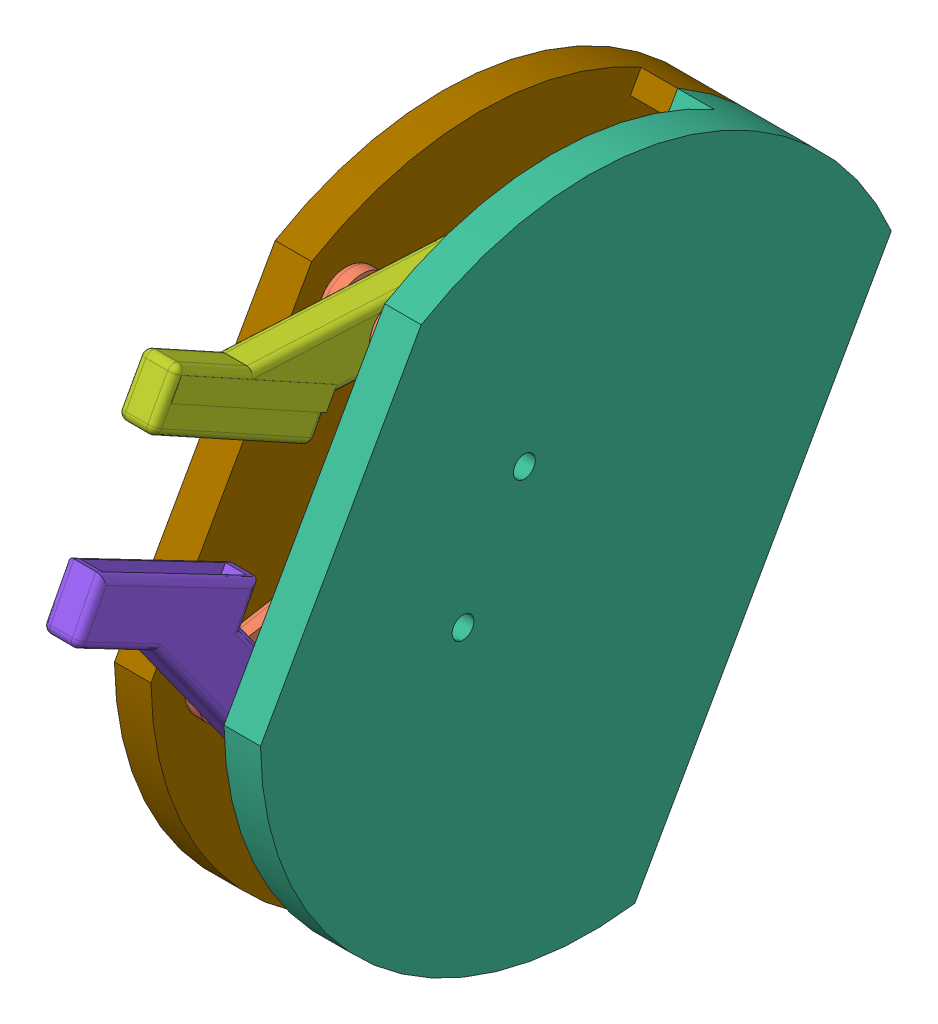
SolidWorks assembly 装配体1, configuration 默认. Lengths in mm.
Overall size (42.8 111.03 110.52).
10 component instances, 9 part files, 24 mates.
Components (placement in the parent):
- microservoArm-1: microservoArm [A3] at (-72.5456 -35.5156 22.831) x (0 -0.510048 -0.860146) z (0 0.860146 -0.510048) size (7.9 3.9 7)
- rod02-1: rod02 [默认] at (-67.7456 -24.2363 68.652) x (0 0.984777 0.173822) z (0 -0.173822 0.984777) size (8 10 28)
- microservoSG90-1: microservoSG90 [Default] at (-102.3456 -39.9562 25.3391) x (0 -0.870717 0.491784) z (0 0.491784 0.870717) size (32.3 29.8 12.5)
- 齿轮-2: 齿轮 [默认] at (-100.0187 -17.6428 -15.5872) x (1 0 0) z (0 -0.892437 -0.451172) size (10 44.73 18.87)
- 齿轮2-2: 齿轮2 [默认] at (-100.0187 -62.2189 6.3465) x (1 0 0) z (0 -0.222605 0.974909) size (10 44.73 18.87)
- rod02-2: rod02 [默认] at (-77.7456 11.5948 50.2917) x (0 -0.487236 0.87327) z (0 0.87327 0.487236) size (8 10 28)
- plate1-3: plate1 [默认] at (-62.7456 -20.692 31.691) x (0 -0.491784 -0.870717) z (0 0.870717 -0.491784) size (66.41 15 90)
- rod03-2: rod03 [默认] at (-75.2456 10.1005 20.329) x (0 0.049811 0.998759) z (0 0.998759 -0.049811) size (67.64 5.02 17.3)
- rod01-3: rod01 [默认] at (-70.2456 -48.6553 51.2247) x (0 0.813966 0.580912) z (0 -0.580912 0.813966) size (68.58 5 17.85)
- plate2-1: plate2 [默认] at (-77.7456 -20.692 31.691) x (0 -0.491784 -0.870717) z (0 0.870717 -0.491784) size (66.41 32.8 90)
Mates (geometry in assembly coordinates):
- 同心4: concentric aligned: circle of microservoArm-1; circle of 齿轮-2
- 平行4: parallel anti-aligned: line of microservoArm-1 through (-72.5456 -38.1899 19.3014) axis (0 -0.860146 0.510048); line of 齿轮-2 through (-69.7456 -40.1794 20.4464) axis (0 0.860146 -0.510048)
- 重合17: coincident anti-aligned: plane of microservoSG90-1 through (-75.7456 -40.5222 25.6588) normal (1 0 0); plane of 齿轮-2 through (-75.7456 -35.5156 22.831) normal (-1 0 0)
- 同心5: concentric aligned: circle of microservoArm-1; circle of microservoSG90-1
- 重合20: coincident aligned: plane of microservoArm-1 through (-72.5456 -27.7629 35.9052) normal (1 0 0); plane of microservoSG90-1 through (-72.5456 -35.5156 22.831) normal (1 0 0)
- 重合26: coincident aligned: plane of 齿轮-2 through (-69.7456 -35.5156 22.831) normal (1 0 0); plane of 齿轮2-2 through (-69.7456 -20.6241 14.4255) normal (1 0 0)
- 同心15: concentric aligned: circle of rod02-1; circle of plate-3
- 同心18: concentric anti-aligned: circle of rod02-2; circle of plate-3
- 重合33: coincident anti-aligned: plane of 齿轮-2 through (-67.7456 -17.6428 -15.5872) normal (1 0 0); plane of plate-3 through (-67.7456 -20.692 31.691) normal (-1 0 0)
- 重合34: coincident anti-aligned: circle of 齿轮-2; circle of rod01-3
- 同心19: concentric aligned: circle of rod02-1; circle of rod01-3
- 同心21: concentric aligned: circle of rod02-2; circle of rod03-2
- 重合35: coincident anti-aligned: plane of 齿轮2-2 through (-70.2456 -62.2189 6.3465) normal (-1 0 0); plane of rod03-2 through (-70.2456 10.1005 20.329) normal (1 0 0)
- 重合36: coincident anti-aligned: plane of rod02-1 through (-75.2456 -28.4155 57.8109) normal (1 0 0); plane of rod01-3 through (-75.2456 -48.6553 51.2247) normal (-1 0 0)
- 同心22: concentric aligned: circle of 齿轮2-2; circle of rod03-2
- 重合37: coincident anti-aligned: plane of rod02-2 through (-75.2456 5.8295 40.2042) normal (1 0 0); plane of rod03-2 through (-75.2456 10.1005 20.329) normal (-1 0 0)
- 平行5: parallel aligned: plane of microservoSG90-1 through (-86.7456 -33.1662 14.3835) normal (0 -0.491784 -0.870717); plane of plate-3 through (-67.7456 -34.1543 7.8555) normal (0 -0.491784 -0.870717)
- 重合39: coincident aligned: plane of plate-3 through (-67.7456 -34.1543 7.8555) normal (0 -0.491784 -0.870717); plane of plate2-1 through (-82.7456 -34.1543 7.8555) normal (0 -0.491784 -0.870717)
- 重合40: coincident anti-aligned: plane of microservoSG90-1 through (-84.1456 -28.9432 11.9984) normal (0 0.870717 -0.491784); plane of plate2-1 through (-102.5456 -28.9432 11.9984) normal (0 -0.870717 0.491784)
- 重合41: coincident anti-aligned: plane of microservoSG90-1 through (-86.7456 -33.1662 14.3835) normal (0 -0.491784 -0.870717); plane of plate2-1 through (-102.5456 -28.9432 11.9984) normal (0 0.491784 0.870717)
- 同心23: concentric aligned: circle of 齿轮2-2; circle of plate-3
- 重合43: coincident aligned: line of plate-3 through (-67.7456 17.9957 54.675) axis (1 0 0); line of plate2-1 through (-82.7456 17.9957 54.675) axis (1 0 0)
- 齿轮配合1: gear = 7 : 7 mm: circle of 齿轮-2; circle of 齿轮2-2
- 重合49: coincident anti-aligned: plane of plate-3 through (-72.7456 -20.692 31.691) normal (-1 0 0); plane of plate2-1 through (-72.7456 -20.692 31.691) normal (1 0 0)
